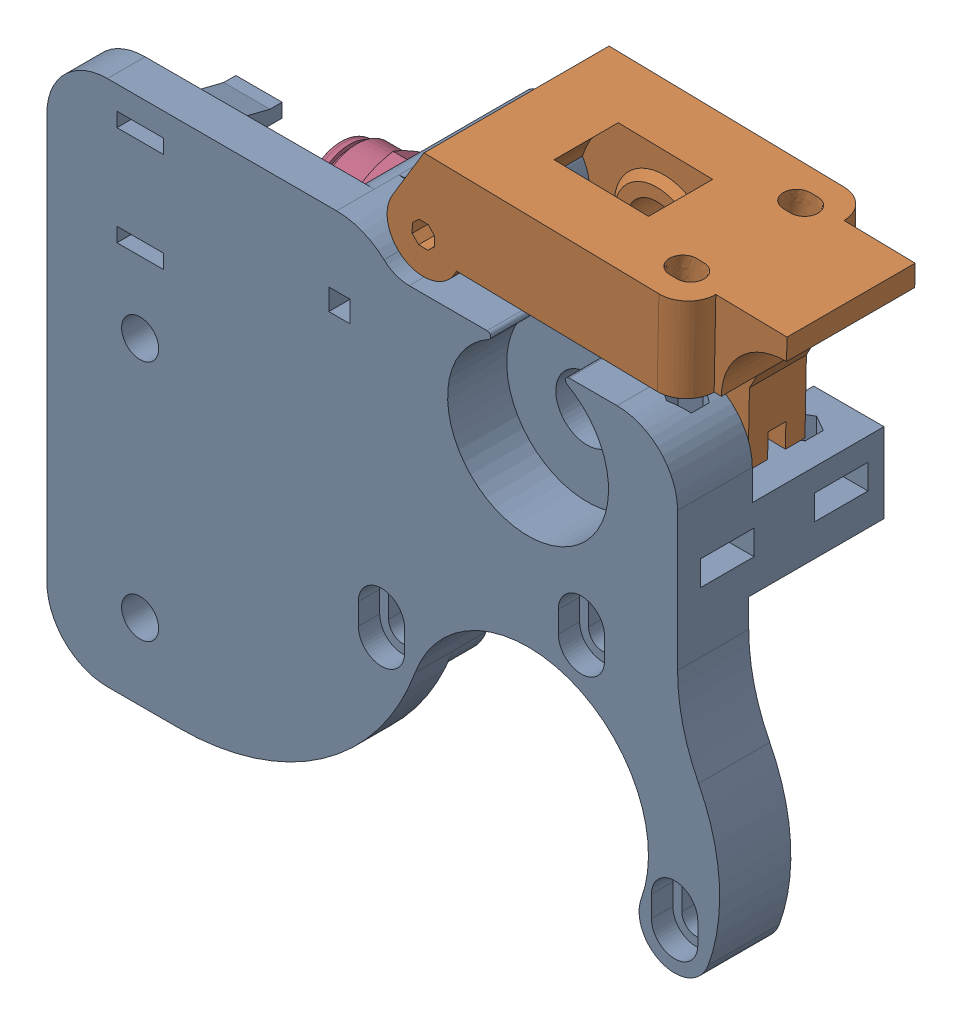
SolidWorks assembly Cold End Assembly, configuration Default. Lengths in mm.
Overall size (97.97 85.38 29).
3 component instances, 3 part files, 8 mates.
Components (placement in the parent):
- Cold End-1: Cold End [Default] x (0 1 0) z (-1 0 0) size (80.9 29 94.51)
- Cold End Hinge-1: Cold End Hinge [Default] at (50.3743 38.4717 -15) x (-0.999806 0.019694 0) z (0 0 1) size (51.98 24.28 26)
- 5225K501-1: 5225K501 [5225K501] at (4.5 16.7 -15) x (0 0 -1) z (1 0 0) size (13 15.01 16.08)
Mates (geometry in assembly coordinates):
- Concentric1: concentric: cylinder of Cold End-1 through (13.3 29.2 -29) axis (0 0 1) radius 2.2; point of Cold End Hinge-1
- Width1: width anti-aligned: plane of Cold End Hinge-1 through (13.3 29.2 -8.5) normal (0 0 -1); plane of Cold End Hinge-1 through (13.3 29.2 -21.5) normal (0 0 1); plane of Cold End-1 through (29.4029 26.1197 -8.75) normal (0 0 1); plane of Cold End-1 through (29.4029 26.1197 -21.25) normal (0 0 -1)
- Coincident2: coincident anti-aligned: plane of Cold End-1; plane of assembly through (0 0 0) normal (0 0 1)
- Coincident3: coincident aligned: plane of Cold End-1; plane of assembly through (0 0 0) normal (0 1 0)
- Coincident5: coincident anti-aligned: plane of Cold End-1 through (0 0 0) normal (-1 0 0); plane of assembly through (0 0 0) normal (1 0 0)
- Coincident6: coincident anti-aligned: plane of Cold End-1 through (0 -20.2279 -106.3912) normal (-1 0 0); plane of 5225K501-1 through (0 27.9583 -21.5) normal (1 0 0)
- Concentric2: concentric anti-aligned: circle of Cold End-1; circle of 5225K501-1
- Parallel1: parallel aligned: plane of Cold End-1 through (30 -28.5 -29) normal (0 0 -1); plane of 5225K501-1 through (-4.55 20.4528 -21.5) normal (0 0 -1)
